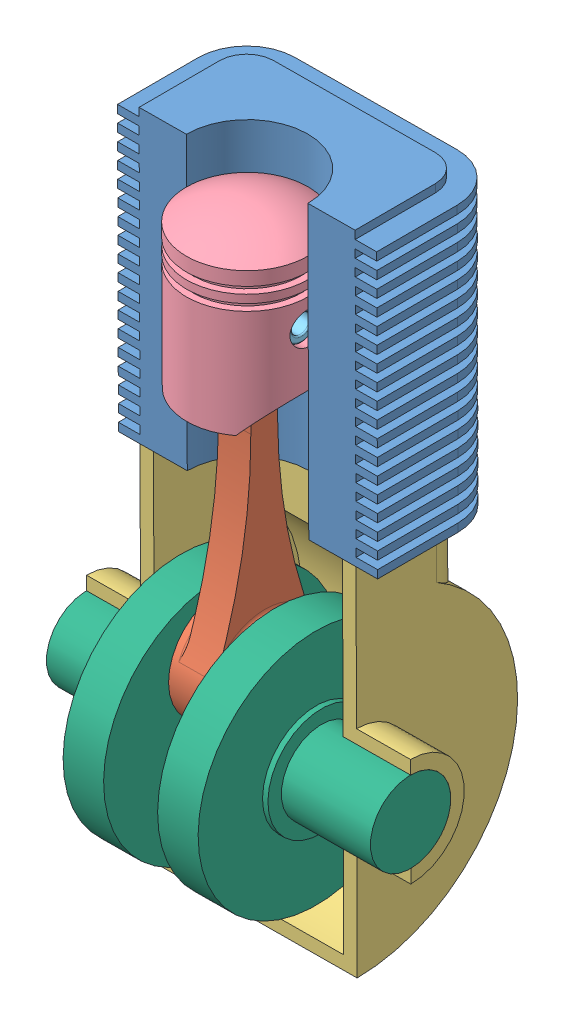
SolidWorks assembly Złożenie_dół_góra, configuration Domyślna. Lengths in mm.
Overall size (120.82 240.51 105.08).
6 component instances, 6 part files, 11 mates.
Components (placement in the parent):
- Cylinder-1: Cylinder [Domyślna] at (-129.2481 74.5895 188.9344) x (-0.999986 -0.004194 0.003247) z (0.004197 -0.999991 0.000991) size (96 48 108)
- Korbowód-1: Korbowód [Domyślna] at (-129.0307 22.588 188.7234) x (0.003252 -0.001183 0.999994) z (-0.999986 -0.004194 0.003247) size (40 151 20)
- Obudowa-1: Obudowa [Domyślna] at (-163.9454 2.4434 189.1194) x (0.003242 0.001005 0.999994) z (-0.999986 -0.004194 0.003247) size (60 132 120)
- Tłok-1: Tłok [60] at (-129.4076 112.5871 188.8967) x (0.003242 0.001005 0.999994) z (-0.999986 -0.004194 0.003247) size (45 62.26 45)
- Trzpień-1: Trzpień [Domyślna] at (-149.5332 142.503 188.9319) x (0.003042 0.047917 0.998847) z (-0.999986 -0.004194 0.003247) size (12 12 40)
- Wał-1: Wał [Domyślna] at (-155.9455 2.4769 189.0934) x (0.003187 0.014131 0.999895) z (-0.999986 -0.004194 0.003247) size (88 88 120)
Mates (geometry in assembly coordinates):
- Wspólnie4: coincident anti-aligned: plane of Cylinder-1 through (-129.2481 74.5895 188.9344) normal (0.004197 -0.999991 0.000991); plane of Obudowa-1 through (-169.2475 74.4217 189.0643) normal (-0.004197 0.999991 -0.000991)
- Wspólnie5: coincident aligned: plane of Cylinder-1 through (-89.7019 182.7562 188.6975) normal (0.003242 0.001005 0.999994); plane of Obudowa-1 through (-69.0307 22.8416 188.7912) normal (0.003242 0.001005 0.999994)
- Wspólnie6: coincident aligned: plane of Cylinder-1 through (-89.8316 182.716 148.6977) normal (0.999986 0.004194 -0.003247); plane of Obudowa-1 through (-88.9464 2.7579 188.8759) normal (0.999986 0.004194 -0.003247)
- Szerokość2: width aligned: plane of Trzpień-1 through (-109.5338 142.6707 188.8021) normal (0.999986 0.004194 -0.003247); plane of Trzpień-1 through (-149.5332 142.503 188.9319) normal (-0.999986 -0.004194 0.003247); plane of Tłok-1 through (-139.5333 142.5449 188.8995) normal (0.999986 0.004194 -0.003247); plane of Tłok-1 through (-119.5336 142.6288 188.8345) normal (-0.999986 -0.004194 0.003247)
- Koncentryczne1: concentric aligned: cylinder of Tłok-1 through (-107.0338 142.6812 188.7939) axis (-0.999986 -0.004194 0.003247) radius 6; cylinder of Trzpień-1 through (-109.5338 142.6707 188.8021) axis (-0.999986 -0.004194 0.003247) radius 6
- Koncentryczne2: concentric anti-aligned: cylinder of Cylinder-1 through (-129.7014 182.5885 188.8273) axis (0.004197 -0.999991 0.000991) radius 22.5; cylinder of Tłok-1 through (-129.6594 172.5866 188.8372) axis (-0.004197 0.999991 -0.000991) radius 22.5
- Koncentryczne3: concentric aligned: cylinder of Obudowa-1 through (-188.945 2.3385 189.2006) axis (0.999986 0.004194 -0.003247) radius 15; cylinder of Wał-1 through (-188.945 2.3385 189.2006) axis (0.999986 0.004194 -0.003247) radius 15
- Wspólnie7: coincident aligned: plane of Obudowa-1 through (-188.945 2.3385 189.2006) normal (-0.999986 -0.004194 0.003247); plane of Wał-1 through (-188.945 2.3385 189.2006) normal (-0.999986 -0.004194 0.003247)
- Wspólnie8: coincident anti-aligned: circle of Korbowód-1; circle of Wał-1
- Wspólnie9: coincident aligned: circle of Korbowód-1; circle of Tłok-1
- Limit odległości1: limit distance = 37.998 mm anti-aligned: plane of Tłok-1 through (-129.4076 112.5871 188.8967) normal (-0.004197 0.999991 -0.000991); plane of Cylinder-1 through (-129.2481 74.5895 188.9344) normal (0.004197 -0.999991 0.000991)
